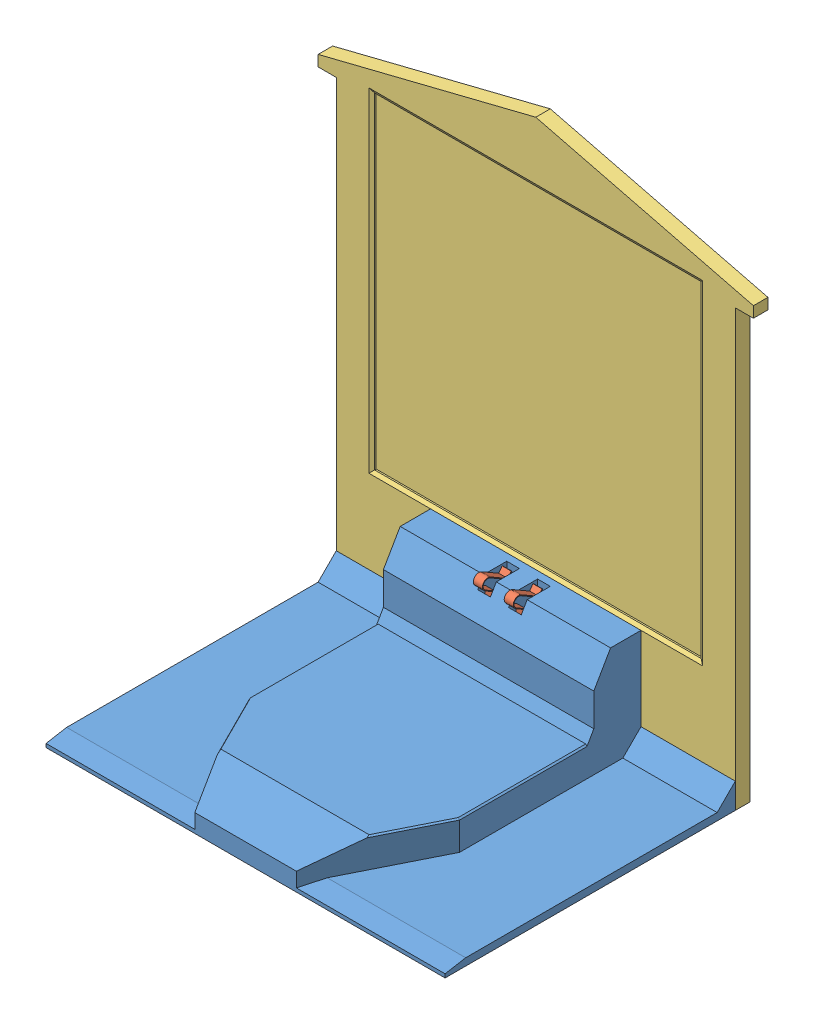
SolidWorks assembly 装配体-充电座, configuration Default. Lengths in mm.
Overall size (120 138 84).
4 component instances, 3 part files, 11 mates.
Components (placement in the parent):
- 充电座-底板-1: 充电座-底板 [Default] at (52.9061 50.7525 71.1528) size (110 30 80)
- 充电粗触片-1: 充电粗触片 [Default] at (47.4061 46.9177 40.468) x (0 0 -1) z (0 -1 0) size (16.65 2.5 26.67)
- 充电粗触片-2: 充电粗触片 [Default] at (55.9061 46.9177 40.468) x (0 0 -1) z (0 -1 0) size (16.65 2.5 26.67)
- 充电座-二维码-1: 充电座-二维码 [Default] at (52.9061 50.7525 29.1528) size (120 138 4)
Mates (geometry in assembly coordinates):
- 重合1: coincident: plane of 充电座-底板-1 through (52.9061 55.9525 71.1528) normal (0 -1 0); plane of 充电粗触片-2 through (58.4061 55.9525 45.1528) normal (0 1 0)
- 平行1: parallel: line of 充电座-底板-1 through (67.9061 50.7525 33.1528) axis (0 0 1); line of 充电粗触片-2 through (55.9061 55.7525 45.3528) axis (0 0 -1)
- 重合3: coincident: plane of 充电座-底板-1 through (67.9061 55.7525 45.1528) normal (0 0 1); plane of 充电粗触片-2 through (58.4061 59.8525 45.1528) normal (0 0 -1)
- 重合4: coincident: plane of 充电座-底板-1 through (52.9061 55.9525 71.1528) normal (0 -1 0); plane of 充电粗触片-1 through (49.9061 55.9525 45.1528) normal (0 1 0)
- 平行2: parallel: line of 充电座-底板-1 through (67.9061 50.7525 33.1528) axis (0 0 1); line of 充电粗触片-1 through (47.4061 55.7525 45.3528) axis (0 0 -1)
- 重合8: coincident: plane of 充电座-底板-1 through (67.9061 55.7525 45.1528) normal (0 0 1); plane of 充电粗触片-1 through (49.9061 59.8525 45.1528) normal (0 0 -1)
- 重合14: coincident: plane of 充电座-底板-1 through (58.4061 55.9525 42.1528) normal (-1 0 0); plane of 充电粗触片-2 through (58.4061 80.9241 41.3626) normal (1 0 0)
- 重合15: coincident: plane of 充电座-底板-1 through (49.9061 55.9525 42.1528) normal (-1 0 0); plane of 充电粗触片-1 through (49.9061 80.9241 41.3626) normal (1 0 0)
- 重合16: coincident: plane of 充电座-底板-1 through (107.9061 52.7525 31.1528) normal (0 0 -1); plane of 充电座-二维码-1 through (107.9061 170.7525 31.1528) normal (0 0 1)
- 同心3: concentric: circle of 充电座-底板-1; circle of 充电座-二维码-1
- 同心4: concentric: circle of 充电座-底板-1; circle of 充电座-二维码-1
